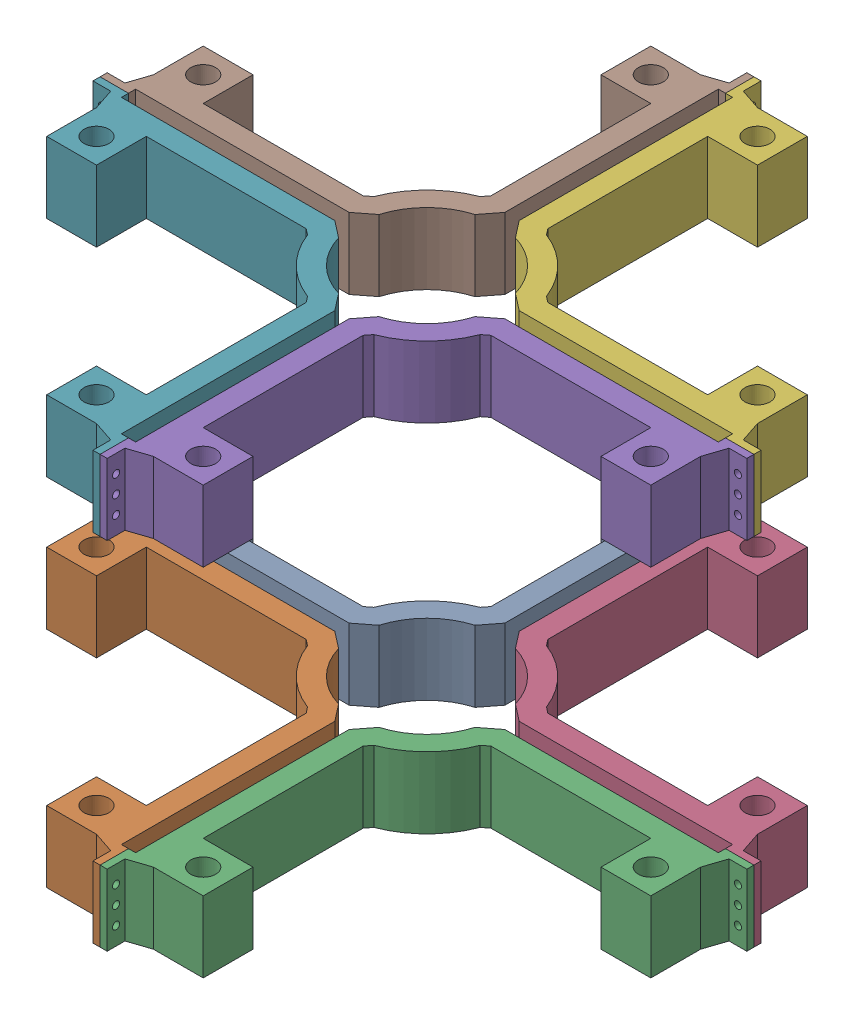
SolidWorks assembly soportes aletas integradas, configuration Default. Lengths in mm.
Overall size (459.58 300 459.58).
8 component instances, 1 part files, 24 mates.
Components (placement in the parent):
- soporte aletas integradas-17: soporte aletas integradas [Default] at (-35.4799 26.302 -1.493) size (229.79 50 229.79)
- soporte aletas integradas-19: soporte aletas integradas [Default] at (-35.4799 76.302 214.0571) x (1 0 0) z (0 0 -1) size (229.79 50 229.79)
- soporte aletas integradas-20: soporte aletas integradas [Default] at (179.3088 26.302 214.0571) x (-1 0 0) z (0 0 -1) size (229.79 50 229.79)
- soporte aletas integradas-21: soporte aletas integradas [Default] at (179.3088 76.302 -1.493) x (-1 0 0) z (0 0 1) size (229.79 50 229.79)
- soporte aletas integradas-26: soporte aletas integradas [Default] at (179.3088 276.302 214.0571) x (-1 0 0) z (0 0 -1) size (229.79 50 229.79)
- soporte aletas integradas-27: soporte aletas integradas [Default] at (179.3088 326.302 -1.493) x (-1 0 0) z (0 0 1) size (229.79 50 229.79)
- soporte aletas integradas-28: soporte aletas integradas [Default] at (-35.4799 326.302 214.0571) x (1 0 0) z (0 0 -1) size (229.79 50 229.79)
- soporte aletas integradas-29: soporte aletas integradas [Default] at (-35.4799 276.302 -1.493) size (229.79 50 229.79)
Mates (geometry in assembly coordinates):
- Coincident2: coincident aligned: plane of soporte aletas integradas-19 through (-35.4799 26.302 336.0707) normal (0 0 1); plane of soporte aletas integradas-20 through (179.3088 76.302 336.0707) normal (0 0 1)
- Coincident3: coincident aligned: plane of soporte aletas integradas-19 through (-35.4799 76.302 214.0571) normal (0 1 0); plane of soporte aletas integradas-20 through (179.3088 76.302 214.0571) normal (0 1 0)
- Coincident4: coincident anti-aligned: plane of soporte aletas integradas-19 through (71.9144 26.302 214.0571) normal (1 0 0); plane of soporte aletas integradas-20 through (71.9144 76.302 214.0571) normal (-1 0 0)
- Coincident5: coincident aligned: plane of soporte aletas integradas-20 through (301.7031 76.302 214.0571) normal (1 0 0); plane of soporte aletas integradas-21 through (301.7031 26.302 -1.493) normal (1 0 0)
- Coincident6: coincident aligned: plane of soporte aletas integradas-20 through (179.3088 76.302 214.0571) normal (0 1 0); plane of soporte aletas integradas-21 through (179.3088 76.302 -1.493) normal (0 1 0)
- Coincident7: coincident anti-aligned: plane of soporte aletas integradas-20 through (179.3088 76.302 106.282) normal (0 0 -1); plane of soporte aletas integradas-21 through (179.3088 26.302 106.282) normal (0 0 1)
- Coincident8: coincident anti-aligned: plane of soporte aletas integradas-17 through (-35.4799 76.302 106.282) normal (0 0 1); plane of soporte aletas integradas-19 through (-35.4799 26.302 106.282) normal (0 0 -1)
- Coincident9: coincident aligned: plane of soporte aletas integradas-17 through (-35.4799 76.302 -1.493) normal (0 1 0); plane of soporte aletas integradas-19 through (-35.4799 76.302 214.0571) normal (0 1 0)
- Coincident10: coincident aligned: plane of soporte aletas integradas-17 through (-157.8742 76.302 -1.493) normal (-1 0 0); plane of soporte aletas integradas-19 through (-157.8742 26.302 214.0571) normal (-1 0 0)
- Coincident13: coincident anti-aligned: plane of soporte aletas integradas-24 through (-249.0017 442.7851 711.9376) normal (0 0 -1); plane of soporte aletas integradas-25 through (-249.0017 492.7851 711.9376) normal (0 0 1)
- Coincident18: coincident aligned: plane of soporte aletas integradas-24 through (-249.0017 492.7851 819.7126) normal (0 1 0); plane of soporte aletas integradas-25 through (-249.0017 492.7851 604.1626) normal (0 1 0)
- Coincident19: coincident aligned: plane of soporte aletas integradas-24 through (-371.396 442.7851 819.7126) normal (-1 0 0); plane of soporte aletas integradas-25 through (-371.396 492.7851 604.1626) normal (-1 0 0)
- Coincident20: coincident anti-aligned: plane of soporte aletas integradas-26 through (179.3088 376.302 106.282) normal (0 0 -1); plane of soporte aletas integradas-27 through (179.3088 326.302 106.282) normal (0 0 1)
- Coincident21: coincident aligned: plane of soporte aletas integradas-26 through (179.3088 376.302 336.0707) normal (0 0 1); plane of soporte aletas integradas-28 through (-35.4799 326.302 336.0707) normal (0 0 1)
- Coincident22: coincident anti-aligned: plane of soporte aletas integradas-28 through (-35.4799 326.302 106.282) normal (0 0 -1); plane of soporte aletas integradas-29 through (-35.4799 376.302 106.282) normal (0 0 1)
- Coincident23: coincident aligned: plane of soporte aletas integradas-26 through (179.3088 376.302 214.0571) normal (0 1 0); plane of soporte aletas integradas-27 through (179.3088 376.302 -1.493) normal (0 1 0)
- Coincident24: coincident anti-aligned: plane of soporte aletas integradas-26 through (71.9144 376.302 214.0571) normal (-1 0 0); plane of soporte aletas integradas-28 through (71.9144 326.302 214.0571) normal (1 0 0)
- Coincident25: coincident aligned: plane of soporte aletas integradas-26 through (301.7031 376.302 214.0571) normal (1 0 0); plane of soporte aletas integradas-27 through (301.7031 326.302 -1.493) normal (1 0 0)
- Coincident26: coincident aligned: plane of soporte aletas integradas-26 through (179.3088 376.302 214.0571) normal (0 1 0); plane of soporte aletas integradas-28 through (-35.4799 376.302 214.0571) normal (0 1 0)
- Coincident27: coincident aligned: plane of soporte aletas integradas-28 through (-35.4799 376.302 214.0571) normal (0 1 0); plane of soporte aletas integradas-29 through (-35.4799 376.302 -1.493) normal (0 1 0)
- Coincident28: coincident aligned: plane of soporte aletas integradas-28 through (-157.8742 326.302 214.0571) normal (-1 0 0); plane of soporte aletas integradas-29 through (-157.8742 376.302 -1.493) normal (-1 0 0)
- Concentric1: concentric aligned: circle of soporte aletas integradas-17; circle of soporte aletas integradas-29
- Concentric2: concentric aligned: circle of soporte aletas integradas-20; circle of soporte aletas integradas-26
- Distance3: distance = 200 mm anti-aligned: plane of soporte aletas integradas-28 through (-35.4799 276.302 214.0571) normal (0 -1 0); plane of soporte aletas integradas-19 through (-35.4799 76.302 214.0571) normal (0 1 0)
